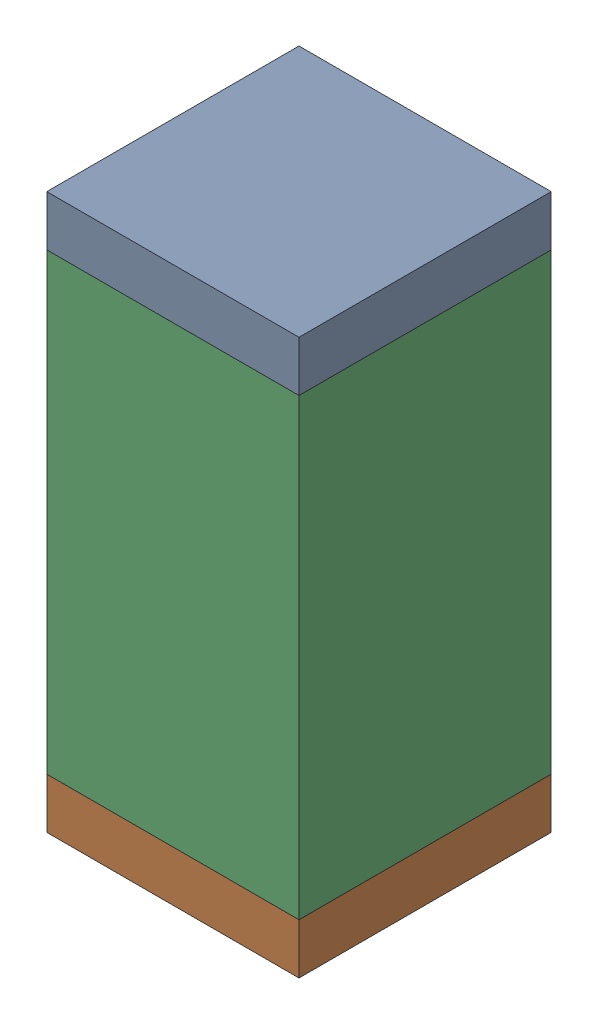
SolidWorks assembly C51, configuration Default. Lengths in mm.
Overall size (0.5 1.1 0.5).
6 component instances, 2 part files, 0 mates.
Components (placement in the parent):
- 810157360-1: 810157360 [Default] at (122.4 44.15 0) size (0.5 0.1 0.5)
  - Extruded_9-1: Extruded_9 [Default] at origin size (0.5 0.1 0.5)
- 810157360-2: 810157360 [Default] at (122.4 43.15 0) size (0.5 0.1 0.5)
  - Extruded_9-1: Extruded_9 [Default] at origin size (0.5 0.1 0.5)
- 791586336-1: 791586336 [Default] at (122.4 43.65 0) size (0.5 0.9 0.5)
  - Extruded_8-1: Extruded_8 [Default] at origin size (0.5 0.9 0.5)
